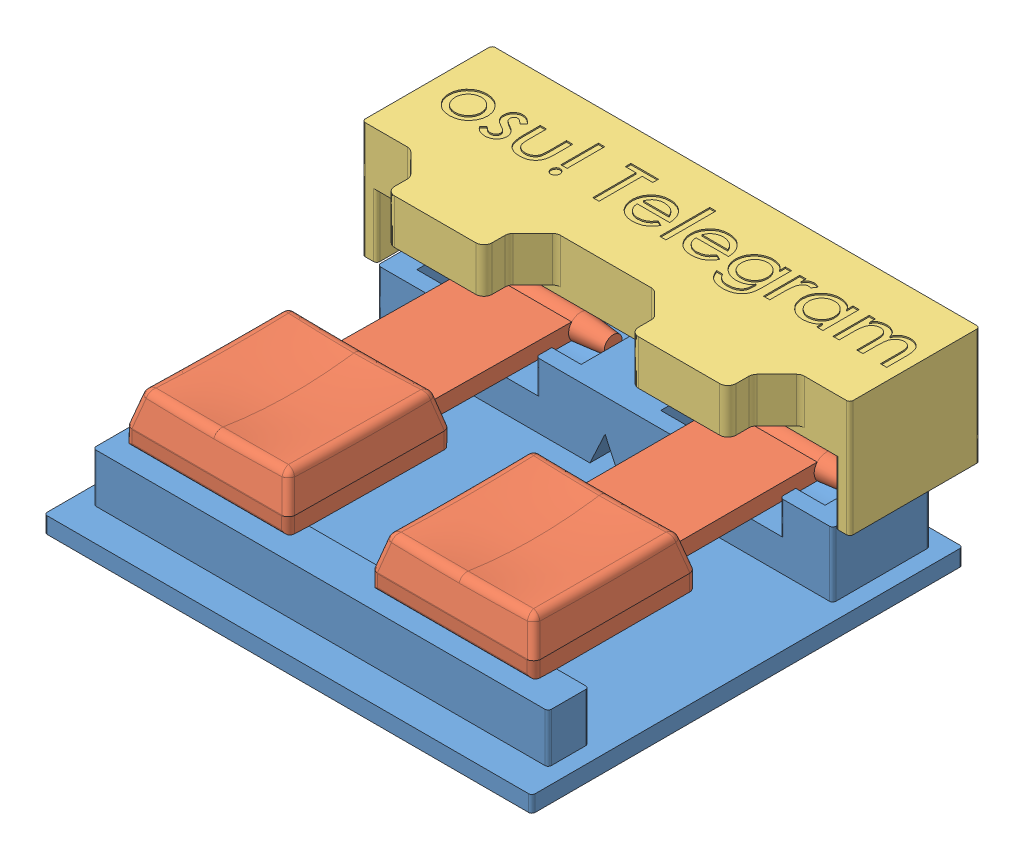
SolidWorks assembly keypad assembly, configuration Default. Lengths in mm.
Overall size (60.01 24.35 55.09).
4 component instances, 3 part files, 3 mates.
Components (placement in the parent):
- case bottom-1: case bottom [Default] at origin size (60 10 53)
- key-1: key [Default] at (15 10 -45) x (1 0 0) z (0 0.01072 0.999943) size (20 6.56 41.5)
- key-2: key [Default] at (45 9.978 -45.2101) size (20 6.56 41.5)
- case top-1: case top [Default] at (60.012 24.3453 -39.0897) x (-1 0 0) z (0 0 -1) size (60 14.3 22)
Mates (geometry in assembly coordinates):
- Concentric1: concentric aligned: circle of case bottom-1; circle of key-1
- Width1: width aligned: plane of case bottom-1 through (25.1 10 -45) normal (-1 0 0); plane of case bottom-1 through (4.9 10 -45) normal (1 0 0); plane of key-1 through (5 10 -45) normal (-1 0 0); plane of key-1 through (25 10 -45) normal (1 0 0)
- Width2: width anti-aligned: plane of case bottom-1 through (55.1 10 -45) normal (-1 0 0); plane of case bottom-1 through (34.9 10 -45) normal (1 0 0); plane of key-2 through (55 9.978 -45.2101) normal (1 0 0); plane of key-2 through (35 9.978 -45.2101) normal (-1 0 0)
